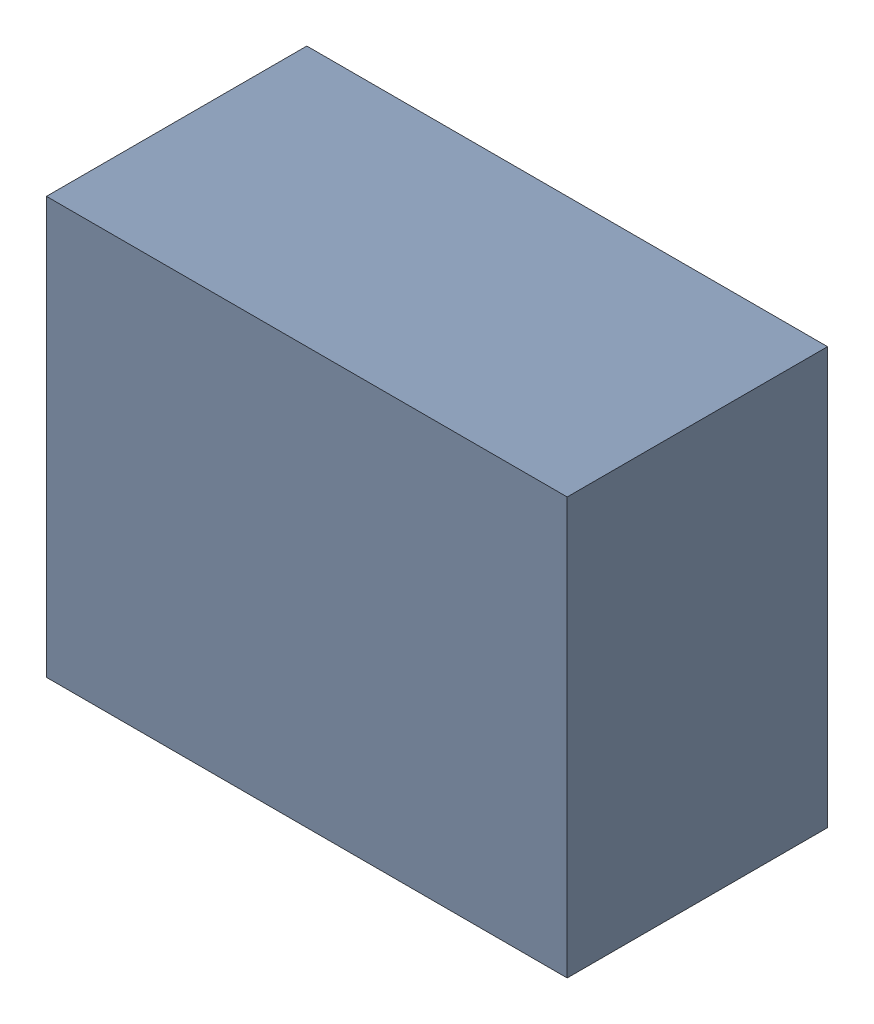
SolidWorks assembly D5, configuration Default. Lengths in mm.
Overall size (1 0.8 0.5).
2 component instances, 1 part files, 0 mates.
Components (placement in the parent):
- 870940960-1: 870940960 [Default] at (35.166 32.031 0) size (1 0.8 0.5)
  - Extruded_33-1: Extruded_33 [Default] at origin size (1 0.8 0.5)
